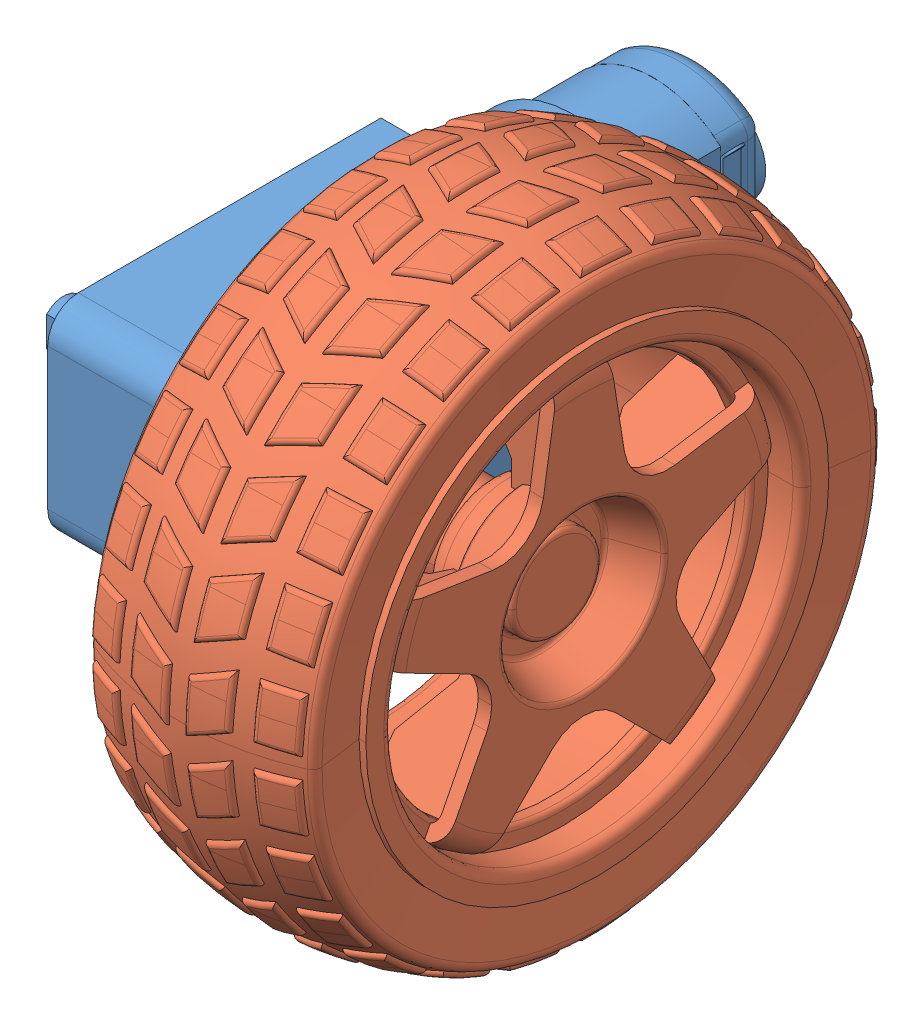
SolidWorks assembly Motor and Wheel, configuration Default. Lengths in mm.
Overall size (57.95 69.08 87.78).
2 component instances, 2 part files, 2 mates.
Components (placement in the parent):
- Motor-1: Motor [Default] at (43.2822 36.5956 -6.1414) size (37.2 22.5 65.5)
- Wheel-1: Wheel [Default] at (82.6322 37.3457 -18.4581) x (0 0 -1) z (1 0 0) size (69.1 69.08 30)
Mates (geometry in assembly coordinates):
- Parallel1: parallel: plane of Motor-1 through (61.8822 36.5956 -17.1414) normal (1 0 0); plane of Wheel-1 through (76.1322 37.3457 -18.4581) normal (-1 0 0)
- Coincident2: coincident anti-aligned: plane of Motor-1 through (52.6322 47.8456 -6.1414) normal (1 0 0); plane of Wheel-1 through (52.6322 37.3457 -18.4581) normal (-1 0 0)
